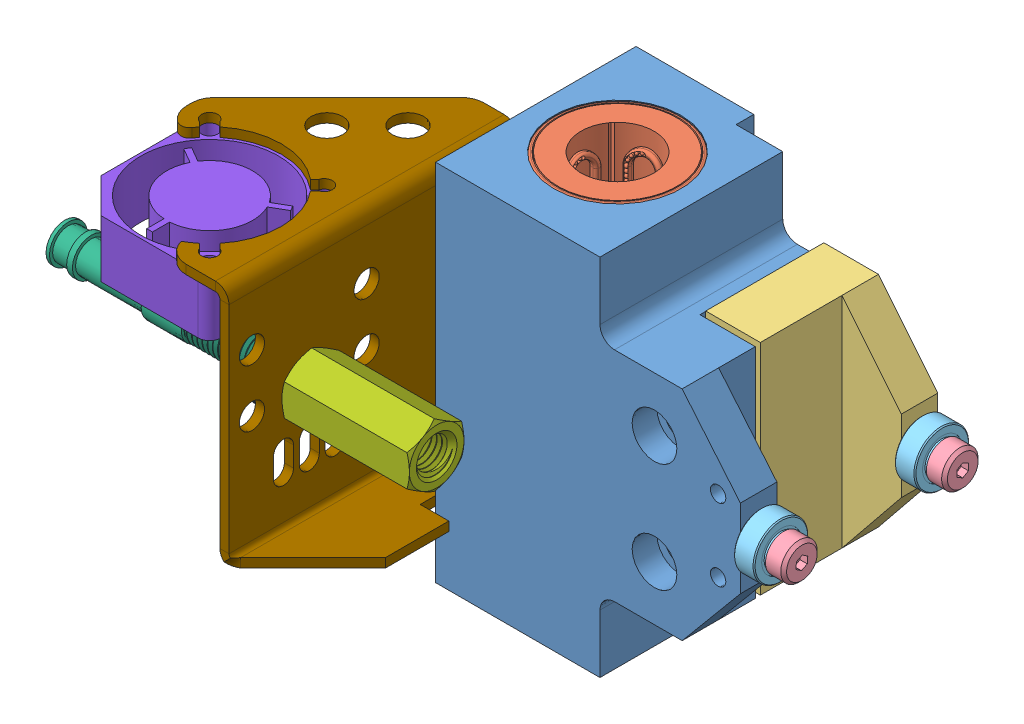
SolidWorks assembly D_Master_01, configuration Default. Lengths in mm.
Overall size (114.21 63.53 63.88).
15 component instances, 10 part files, 21 mates.
Components (placement in the parent):
- D0001-1: D0001 [Default] at origin size (70.91 63.53 34.98)
- 1-2in_ss_60595K730-1: 1-2in_ss_60595K730 [60595K73] at (0 15.89 0) x (0.932866 0 0.360224) z (0 1 0) size (22.23 22.23 31.75)
- 1-2in_ss_60595K730-2: 1-2in_ss_60595K730 [60595K73] at (0 -15.89 0) x (1 0 0) z (0 1 0) size (22.23 22.23 31.75)
- D0002-2: D0002 [Default] at (38.9 0 -13.79) x (0 0 1) z (0 -1 0) size (20.61 19.87 38.18)
- Shoulder_1-8x1-8_4-40_94035A511-1: Shoulder_1-8x1-8_4-40_94035A511 [94035A511] at (43.2663 0 -13.79) x (0 -0.860721 -0.509076) z (0 -0.509076 0.860721) size (6.35 10.59 6.35)
- Shoulder_1-8x1-8_4-40_94035A511-2: Shoulder_1-8x1-8_4-40_94035A511 [94035A511] at (43.2063 0 14.215) x (0 -0.89841 -0.439157) z (0 -0.439157 0.89841) size (6.35 10.59 6.35)
- 1-8x3-8x9-64_ss_eir-57155K140-1: 1-8x3-8x9-64_ss_eir-57155K140 [57155K14] at (41.0831 0 -13.79) x (0 0.337515 -0.94132) z (1 0 0) size (9.53 9.53 4.37)
- 1-8x3-8x9-64_ss_eir-57155K140-2: 1-8x3-8x9-64_ss_eir-57155K140 [57155K14] at (41.0231 0 14.215) x (0 0.0696 -0.997575) z (1 0 0) size (9.53 9.53 4.37)
- Nozzle_02-1: Nozzle_02 [Default] at (-23.77 0 0) x (1 0 0) z (0 0 -1) size (106.61 63.53 61.4)
  - D0001-1: D0001 [Default] at (23.77 0 0) size (70.91 63.53 34.98) (suppressed, hidden)
  - Nozzle_02-2: Nozzle_02 [92196A333] at (6.5217 0 -30) x (0 -0.248007 -0.968758) z (1 0 0) size (7.33 6.63 50.7)
  - Coupling-1-4x28_90268A325-1: Coupling-1-4x28_90268A325 [No machining] at (22.225 0 -30) x (0 0 -1) z (1 0 0) size (9.53 11 22.44)
  - Fan_25x25x10-1: Fan_25x25x10 [Default] at (-17.3813 -14.6069 -30) x (1 0 0) z (0 1 0) size (25 25 10)
  - E_MountPlate^Nozzle_02-1: E_MountPlate^Nozzle_02 [Default] x (0 0 -1) z (1 0 0) size (50.37 42.39 44.81) (virtual)
  - Thin_1-4x28_92101A320-1: Thin_1-4x28_92101A320 [92101A320] at (-5.5563 0 -30) x (0 -0.669166 0.743113) z (-1 0 0) size (11.11 12.83 4.59)
Mates (geometry in assembly coordinates):
- Coincident1: coincident aligned: plane of D0001-1 through (0 0 0) normal (0 0 1); plane of assembly through (0 0 0) normal (0 0 1)
- Coincident2: coincident aligned: plane of D0001-1 through (0 0 0) normal (0 1 0); plane of assembly through (0 0 0) normal (0 1 0)
- Coincident3: coincident aligned: plane of D0001-1 through (0 0 0) normal (1 0 0); plane of assembly through (0 0 0) normal (1 0 0)
- Concentric1: concentric anti-aligned: cylinder of D0001-1 through (0 -31.765 0) axis (0 1 0) radius 11.1; cylinder of 1-2in_ss_60595K730-1 through (0 31.765 0) axis (0 -1 0) radius 11.1125
- Concentric2: concentric anti-aligned: cylinder of D0001-1 through (0 -31.765 0) axis (0 1 0) radius 11.1; cylinder of 1-2in_ss_60595K730-2 through (0 -0.015 0) axis (0 -1 0) radius 11.1125
- Coincident5: coincident aligned: plane of D0001-1 through (-14.34 31.765 -17.58) normal (0 1 0); plane of 1-2in_ss_60595K730-1 through (0 31.765 0) normal (0 1 0)
- Coincident6: coincident aligned: plane of D0001-1 through (-14.34 -31.765 -17.58) normal (0 -1 0); plane of 1-2in_ss_60595K730-2 through (0 -31.765 0) normal (0 -1 0)
- Coincident11: coincident anti-aligned: plane of D0001-1 through (19.03 -31.765 -14.49) normal (1 0 0); plane of D0002-2 through (19.03 19.09 3.64) normal (-1 0 0)
- Distance2: distance = 1 mm anti-aligned: plane of D0002-2 through (28.56 19.09 3.64) normal (0 0 1); plane of D0001-1 through (28.68 -31.765 4.64) normal (0 0 -1)
- Coincident14: coincident anti-aligned: plane of D0002-2 through (38.9 0 -13.79) normal (0 -1 0); plane of assembly through (0 0 0) normal (0 1 0)
- Concentric6: concentric aligned: cylinder of D0002-2 through (32.55 0 -13.79) axis (1 0 0) radius 1.125; cylinder of Shoulder_1-8x1-8_4-40_94035A511-1 through (40.0913 0 -13.79) axis (1 0 0) radius 1.5875
- Concentric7: concentric aligned: cylinder of D0001-1 through (32.49 0 14.215) axis (1 0 0) radius 1.075; cylinder of Shoulder_1-8x1-8_4-40_94035A511-2 through (40.0313 0 14.215) axis (1 0 0) radius 1.5875
- Concentric8: concentric aligned: cylinder of Shoulder_1-8x1-8_4-40_94035A511-1 through (40.0913 0 -13.79) axis (1 0 0) radius 1.5875; cylinder of 1-8x3-8x9-64_ss_eir-57155K140-1 through (42.8687 0 -13.79) axis (1 0 0) radius 1.5875
- Concentric9: concentric aligned: cylinder of Shoulder_1-8x1-8_4-40_94035A511-2 through (40.0313 0 14.215) axis (1 0 0) radius 1.5875; cylinder of 1-8x3-8x9-64_ss_eir-57155K140-2 through (42.8087 0 14.215) axis (1 0 0) radius 1.5875
- Coincident17: coincident anti-aligned: plane of Shoulder_1-8x1-8_4-40_94035A511-1 through (43.2663 0 -13.79) normal (-1 0 0); plane of 1-8x3-8x9-64_ss_eir-57155K140-1 through (43.2663 1.6624 -13.1939) normal (1 0 0)
- Coincident18: coincident anti-aligned: plane of Shoulder_1-8x1-8_4-40_94035A511-2 through (43.2063 0 14.215) normal (-1 0 0); plane of 1-8x3-8x9-64_ss_eir-57155K140-2 through (43.2063 1.7618 14.3379) normal (1 0 0)
- Coincident19: coincident anti-aligned: plane of D0002-2 through (38.9 19.09 -16.97) normal (1 0 0); plane of 1-8x3-8x9-64_ss_eir-57155K140-1 through (38.9 2.5743 -12.867) normal (-1 0 0)
- Coincident20: coincident anti-aligned: plane of D0001-1 through (38.84 -31.765 17.4) normal (1 0 0); plane of 1-8x3-8x9-64_ss_eir-57155K140-2 through (38.84 2.7281 14.4053) normal (-1 0 0)
- Concentric10: concentric anti-aligned: cylinder of D0001-1 through (-13.27 0 0) axis (-1 0 0) radius 2; cylinder of Nozzle_02-1/E_MountPlate^Nozzle_02-1 through (-25.3575 0 0) axis (1 0 0) radius 3.25
- Concentric11: concentric aligned: cylinder of D0001-1 through (-32.07 -9.505 0) axis (1 0 0) radius 1.57; cylinder of Nozzle_02-1/E_MountPlate^Nozzle_02-1 through (-25.3575 -9.505 0) axis (1 0 0) radius 1.57
- Coincident21: coincident anti-aligned: plane of D0001-1 through (-23.77 19.06 -6.365) normal (-1 0 0); plane of Nozzle_02-1/E_MountPlate^Nozzle_02-1 through (-23.77 -23.06 -6.365) normal (1 0 0)
